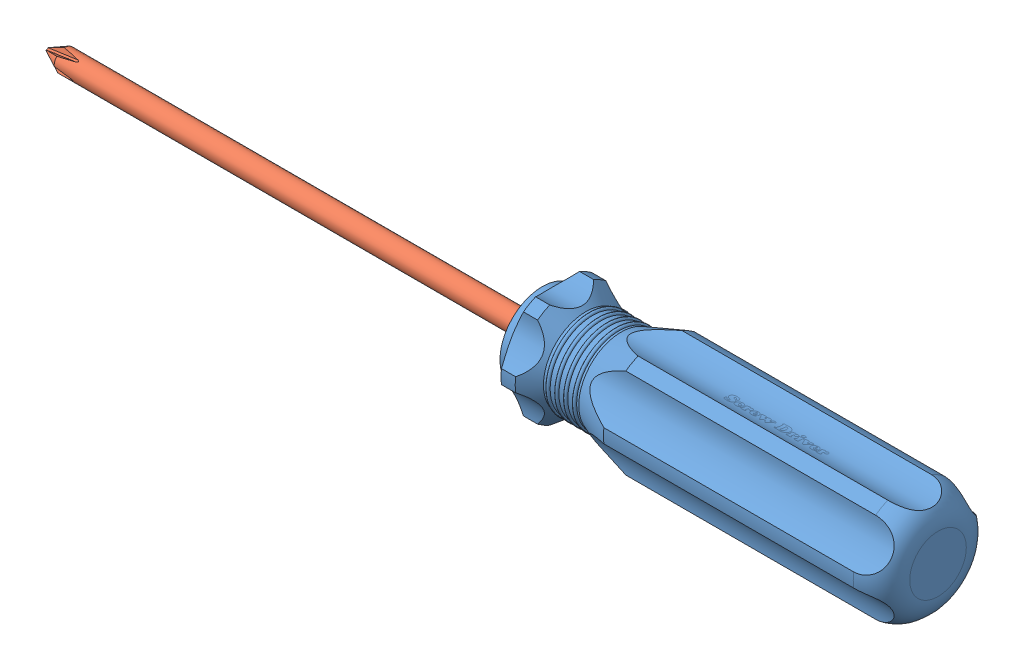
SolidWorks assembly Screw Driver, configuration Default. Lengths in mm.
Overall size (126 15.82 16.96).
2 component instances, 2 part files, 2 mates.
Components (placement in the parent):
- Part1-1: Part1 [Default] at origin size (56 15.82 16.96)
- Part2-2: Part2 [Default] at (-70 0 0) x (1 0 0) z (0 -0.430319 0.902677) size (100 4 4)
Mates (geometry in assembly coordinates):
- Concentric1: concentric: cylinder of Part1-1 through (30 0 0) axis (-1 0 0) radius 1.5; cylinder of Part2-2 through (-70 0 0) axis (-1 0 0) radius 1.5
- Coincident1: coincident anti-aligned: plane of Part1-1 through (30 0 0) normal (-1 0 0); plane of Part2-2 through (30 0 0) normal (1 0 0)
